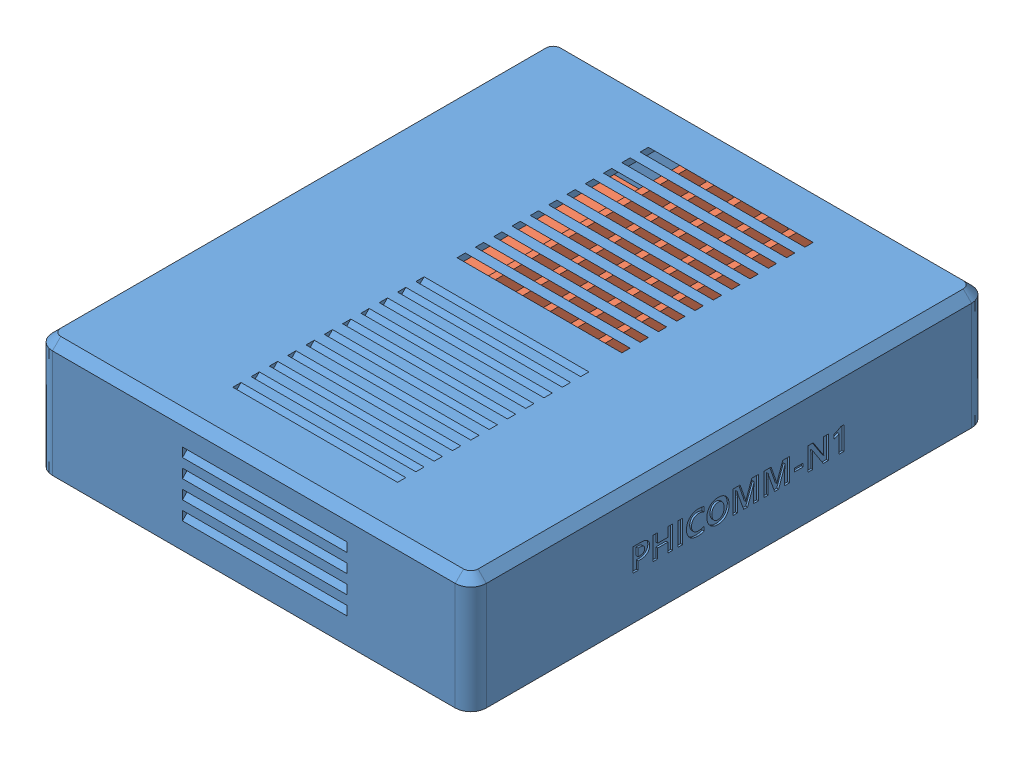
SolidWorks assembly 装配体1, configuration 默认. Lengths in mm.
Overall size (94.8 25.4 112.8).
4 component instances, 4 part files, 8 mates.
Components (placement in the parent):
- top-1: top [默认] at (-79.1747 28.2862 0) size (94.8 25.4 112.8)
- main-board-1: main-board [默认] at (-34.9247 36.1862 -54) x (1 0 0) z (0 0 -1) size (89 20.4 104.61)
- eth-bracket-1: eth-bracket [默认] at (-58.9247 49.1862 35.45) x (0 0 1) z (-1 0 0) size (21 18.7 65)
- bottom-1: bottom [默认] at (-79.1747 32.1619 0) x (0 0 -1) z (-1 0 0) size (109.8 6.45 91.8)
Mates (geometry in assembly coordinates):
- 重合1: coincident anti-aligned: plane of top-1 through (-41.9247 36.1862 40.5) normal (0 -1 0); plane of main-board-1 through (-34.9247 36.1862 -54) normal (0 1 0)
- 同心1: concentric aligned: cylinder of top-1 through (-41.9247 36.1862 40.5) axis (0 1 0) radius 0.75; cylinder of main-board-1 through (-41.9247 34.9862 40.5) axis (0 1 0) radius 1
- 同心2: concentric aligned: cylinder of top-1 through (-41.9247 36.1862 -51.5) axis (0 1 0) radius 0.75; cylinder of main-board-1 through (-41.9247 34.9862 -51.5) axis (0 1 0) radius 1
- 同心3: concentric aligned: cylinder of main-board-1 through (-62.4247 34.9862 37.4) axis (0 1 0) radius 1; cylinder of eth-bracket-1 through (-62.4247 32.4852 37.4) axis (0 1 0) radius 1.25
- 重合2: coincident anti-aligned: plane of main-board-1 through (-34.9247 34.9862 -54) normal (0 -1 0); plane of eth-bracket-1 through (-123.9247 34.9862 50.55) normal (0 1 0)
- 同心4: concentric aligned: cylinder of main-board-1 through (-90.9247 34.9862 37.4) axis (0 1 0) radius 1; cylinder of eth-bracket-1 through (-90.9247 32.4852 37.4) axis (0 1 0) radius 1.25
- 同心7: concentric anti-aligned: cylinder of top-1 through (-41.9247 36.1862 -51.5) axis (0 1 0) radius 0.75; cylinder of bottom-1 through (-41.9247 32.1619 -51.5) axis (0 -1 0) radius 1
- 同心8: concentric anti-aligned: cylinder of top-1 through (-41.9247 36.1862 40.5) axis (0 1 0) radius 0.75; cylinder of bottom-1 through (-41.9247 32.1619 40.5) axis (0 -1 0) radius 1
